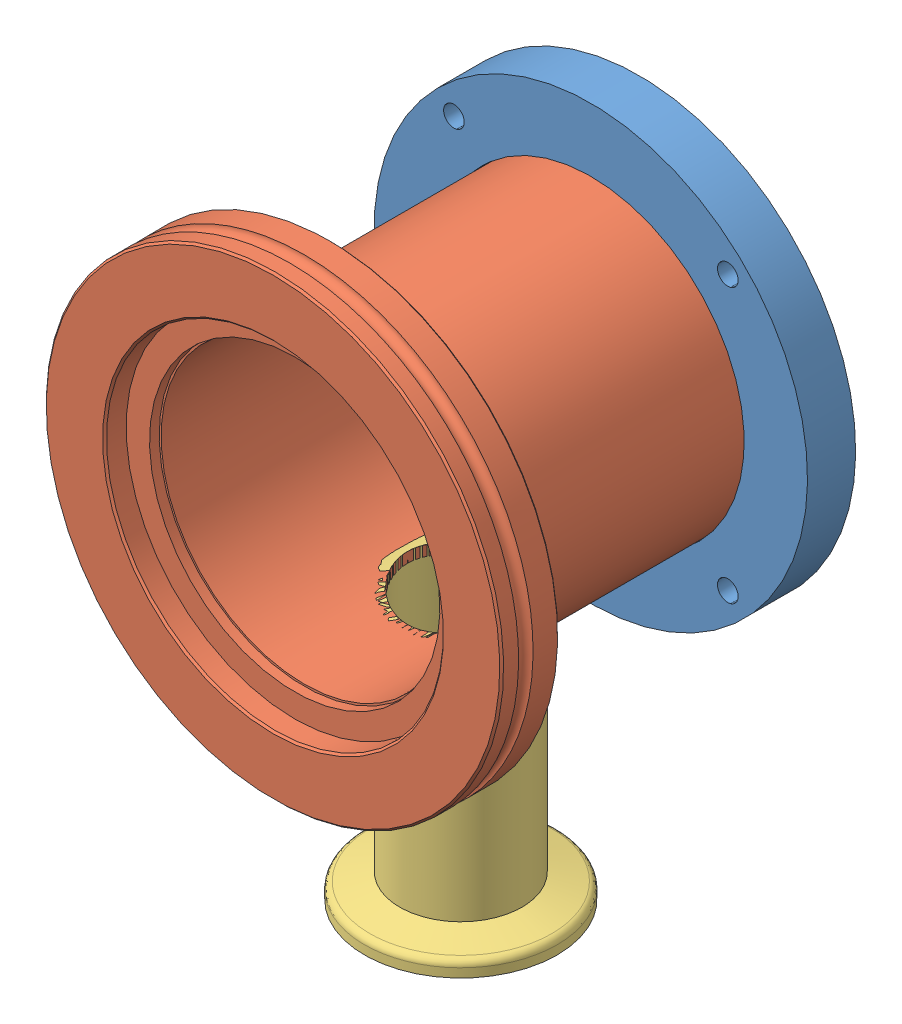
SolidWorks assembly CryostatFlange, configuration Default. Lengths in mm.
Overall size (190.27 206.8 76).
3 component instances, 3 part files, 6 mates.
Components (placement in the parent):
- LowerFlange-4: LowerFlange [Default] x (0.707107 0.707107 0) z (-0.707107 0.707107 0) size (146.12 10 129.28)
- Hositrad_ISO63-64NH-4: Hositrad_ISO63-64NH [Default] at (0 0 76) x (1 0 0) z (0 1 0) size (95 76 95)
- Hositrad_KF25-25-70-5: Hositrad_KF25-25-70 [Default] at (0 -84.706 37) x (0 0 -1) z (1 0 0) size (40 58.62 40)
Mates (geometry in assembly coordinates):
- Parallel1: parallel anti-aligned: plane of LowerFlange-4 through (0 0 0) normal (0 0 -1)
- Coincident1: coincident: point of LowerFlange-4
- Concentric1: concentric anti-aligned: circle of LowerFlange-4; circle of Hositrad_ISO63-64NH-4
- Coincident2: coincident aligned: plane of LowerFlange-4 through (0 0 0) normal (0 0 -1); plane of Hositrad_ISO63-64NH-4 through (31.75 0 0) normal (0 0 -1)
- Concentric2: concentric aligned: circle of Hositrad_ISO63-64NH-4; circle of Hositrad_KF25-25-70-5
- Concentric3: concentric anti-aligned: cylinder of Hositrad_ISO63-64NH-4 through (0 0 -12) axis (0 0 1) radius 29.75; cylinder of Hositrad_KF25-25-70-5 through (0 0 57) axis (0 0 -1) radius 29.75
